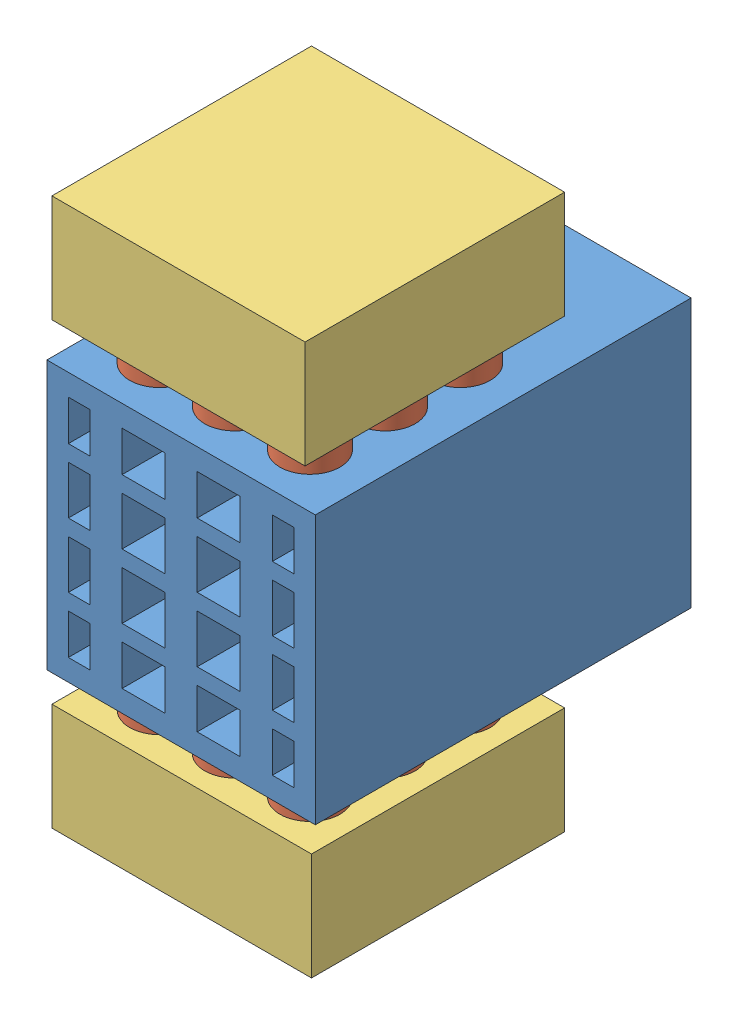
SolidWorks assembly 1.12model, configuration Default. Lengths in mm.
Overall size (50 51 50).
5 component instances, 3 part files, 13 mates.
Components (placement in the parent):
- 插头-正方形底1.11-1: 插头-正方形底1.11 [默认] at (21.6152 20.3473 11.1593) size (25 25 35)
- sensor cyli bump-1: sensor cyli bump [Default] at (21.9003 22.8473 12.6956) x (0 0 -1) z (0 1 0) size (50 30 3)
- sensorbase-1: sensorbase [Default] at (8.178 35.8473 23.5599) x (-1 0 0) z (0 1 0) size (23.58 24.17 10)
- sensor cyli bump-2: sensor cyli bump [Default] at (33.0789 17.8473 23.8742) x (1 0 0) z (0 -1 0) size (50 30 3)
- sensorbase-2: sensorbase [Default] at (21.2446 4.8473 36.6265) x (0 0 1) z (0 -1 0) size (23.58 24.17 10)
Mates (geometry in assembly coordinates):
- 重合2: coincident anti-aligned: plane of 插头-正方形底1.11-1 through (9.1152 32.8473 36.1593) normal (0 1 0); plane of sensor cyli bump-1 through (39.7709 32.8473 37.2081) normal (0 -1 0)
- 重合3: coincident anti-aligned: plane of 插头-正方形底1.11-1 through (9.1152 32.8473 36.1593) normal (0 1 0); plane of sensor cyli bump-1 through (39.7709 32.8473 37.2081) normal (0 -1 0)
- 重合5: coincident aligned: line of 插头-正方形底1.11-1 through (14.6152 32.8473 36.1593) axis (0 0 -1); line of sensor cyli bump-1 through (14.6152 32.8473 37.2081) axis (0 0 -1)
- 重合6: coincident anti-aligned: line of 插头-正方形底1.11-1 through (9.1152 32.8473 31.1593) axis (1 0 0); line of sensor cyli bump-1 through (17.4152 32.8473 31.1593) axis (-1 0 0)
- 重合7: coincident anti-aligned: plane of sensor cyli bump-1 through (28.6152 35.8473 31.1593) normal (0 1 0); plane of sensorbase-1 through (8.178 35.8473 23.5599) normal (0 -1 0)
- 重合8: coincident anti-aligned: plane of 插头-正方形底1.11-1 through (9.1152 7.8473 36.1593) normal (0 -1 0); plane of sensor cyli bump-2 through (8.5664 7.8473 6.0036) normal (0 1 0)
- 重合9: coincident anti-aligned: plane of 插头-正方形底1.11-1 through (9.1152 7.8473 36.1593) normal (0 -1 0); plane of sensor cyli bump-2 through (8.5664 7.8473 6.0036) normal (0 1 0)
- 重合10: coincident aligned: line of 插头-正方形底1.11-1 through (14.6152 7.8473 36.1593) axis (0 0 -1); line of sensor cyli bump-2 through (14.6152 7.8473 31.1593) axis (0 0 -1)
- 重合11: coincident aligned: line of 插头-正方形底1.11-1 through (9.1152 7.8473 31.1593) axis (1 0 0); line of sensor cyli bump-2 through (8.5664 7.8473 31.1593) axis (1 0 0)
- 重合12: coincident aligned: plane of 插头-正方形底1.11-1 through (9.1152 7.8473 36.1593) normal (-1 0 0); plane of sensorbase-1 through (9.1152 120.5819 35.6892) normal (-1 0 0)
- 重合13: coincident anti-aligned: plane of sensor cyli bump-2 through (14.6152 4.8473 24.1593) normal (0 -1 0); plane of sensorbase-2 through (21.2446 4.8473 36.6265) normal (0 1 0)
- 重合14: coincident aligned: plane of sensorbase-1 through (9.1152 120.5819 35.6892) normal (-1 0 0); plane of sensorbase-2 through (9.1152 -5.1527 12.1139) normal (-1 0 0)
- 重合15: coincident aligned: plane of sensorbase-1 through (32.6906 45.8473 35.6892) normal (0 0 1); plane of sensorbase-2 through (9.1152 -79.8873 35.6892) normal (0 0 1)
